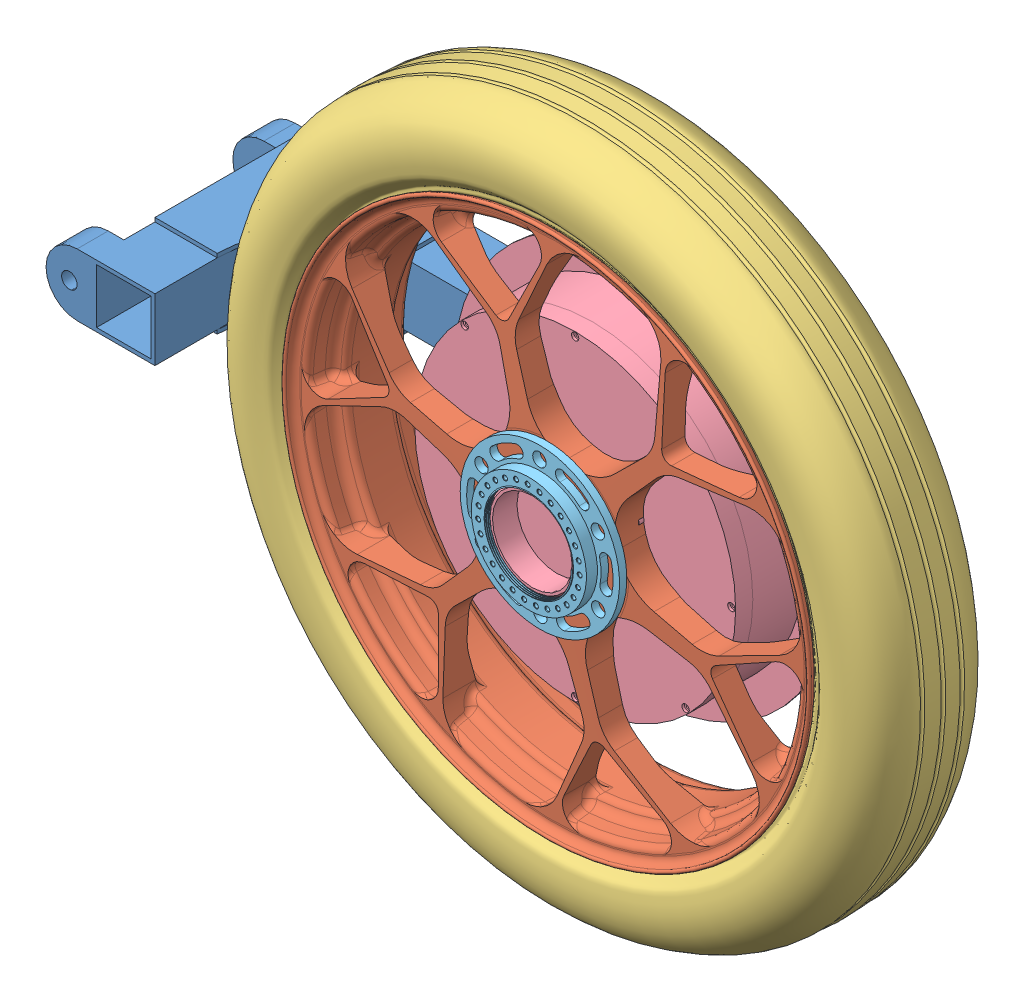
SolidWorks assembly Rear Suspension Assembly, configuration Default. Lengths in mm.
Overall size (682.53 577.66 234.56).
5 component instances, 5 part files, 35 mates.
Components (placement in the parent):
- Rear Fork V2-1: Rear Fork V2 [Default] at origin size (434.11 89.4 177.8)
- rimmachined13-1: rimmachined13 [Default] at (355.6 26.4753 117.375) x (0 0 1) z (0.95959 0.281401 0) size (93.59 431.57 431.57)
- Michelin Tire-2: Michelin Tire [Default] at (355.6 26.4753 117.375) x (0 0 -1) z (0.999256 0.038577 0) size (101.13 556.61 556.61)
- Motor Mitsuba M2096 D-III-1: Motor Mitsuba M2096 D-III [Default] at (355.6 26.4753 125.675) x (1 0 0) z (0 -1 0) size (310 108 310)
- Nut-2: Nut [Default] at (355.6 26.4753 186.0565) x (-1 0 0) z (0 0 -1) size (130 130 98.66)
Mates (geometry in assembly coordinates):
- Concentric2: concentric anti-aligned: cylinder of Spindle_Light-1 through (381 25.4 147.175) axis (0 0 1) radius 8.5; cylinder of SKF_6003-2Z.stp-1 through (381 25.4 143.9729) axis (0 0 -1) radius 8.5
- Concentric4: concentric aligned: cylinder of Hub-1 through (368.3 25.4 -790.8358) axis (0 0 -1) radius 21; cylinder of SKF_6004-2Z.stp-1 through (381 25.4 35.675) axis (0 0 -1) radius 21
- Coincident5: coincident anti-aligned: plane of Hub-1 through (387.1048 22.6835 123.775) normal (0 0 -1); plane of SKF_6004-2Z.stp-1 through (381 45.8 85.675) normal (0 0 1)
- Concentric5: concentric aligned: cylinder of Hub-1 through (368.3 25.4 -790.8358) axis (0 0 -1) radius 17.5; cylinder of SKF_6003-2Z.stp-1 through (381 25.4 143.9729) axis (0 0 -1) radius 17.5
- Coincident6: coincident anti-aligned: plane of Hub-1 through (383.6408 23.1839 158.775) normal (0 0 1); plane of SKF_6003-2Z.stp-1 through (382.3309 40.9431 183.9729) normal (0 0 -1)
- Coincident8: coincident anti-aligned: plane of Spindle_Light-1 through (381 37.4 73.675) normal (0 0 1); plane of SKF_6004-2Z.stp-1 through (381 36 73.675) normal (0 0 -1)
- Concentric6: concentric anti-aligned: cylinder of Hub-1 through (368.3 25.4 -790.8358) axis (0 0 -1) radius 47; cylinder of rimmachined13-1 through (355.6 26.4753 126.475) axis (0 0 1) radius 47
- Coincident9: coincident anti-aligned: plane of Hub-1 through (414.8171 18.6801 153.583) normal (0 0 1); plane of rimmachined13-1 through (366.8561 -11.9084 139.675) normal (0 0 -1)
- Perpendicular1: perpendicular: plane of Rear Fork V2-1 through (0 50.8 177.8) normal (0 1 0); plane of Spindle_Light-1 through (396 6.4835 47.175) normal (1 0 0)
- Concentric9: concentric aligned: cone of Hub-1 through (368.3 25.4 194.9918) axis (0 0 -1); cylinder of Nut-1 through (381 25.4 174.7059) axis (0 0 -1) radius 47
- Coincident13: coincident anti-aligned: plane of Nut-1 through (344.9044 19.9819 201.2743) normal (0 0 -1); plane of rimmachined13-1 through (373.8911 -35.8981 162.47) normal (0 0 1)
- Concentric14: concentric aligned: cylinder of rimmachined13-1 through (355.6 26.4753 31.8658) axis (0 0 -1) radius 192.7898; line of Michelin Tire-2 through (355.6 26.4753 220.0979) axis (0 0 -1)
- Coincident19: coincident: plane of rimmachined13-1 through (355.6 26.4753 117.375) normal (0 0 1); line of Michelin Tire-2 through (346.0008 275.1246 117.375) axis (0.038577 -0.999256 0)
- Concentric15: concentric aligned: cylinder of Hub-1 through (368.3 25.4 -790.8358) axis (0 0 -1) radius 29; cylinder of BasicBrakeDisc-1 through (673.6832 81.5008 299.6671) axis (0 0 -1) radius 28.956
- Coincident20: coincident anti-aligned: plane of Hub-1 through (397.0021 21.2537 113.775) normal (0 0 -1); plane of BasicBrakeDisc-1 through (673.6832 81.5008 299.6671) normal (0 0 1)
- Concentric16: concentric anti-aligned: cylinder of rimmachined13-1 through (355.6 26.4753 126.475) axis (0 0 1) radius 47; cylinder of Rear Hub-1 through (381 25.4 -765.5354) axis (0 0 -1) radius 47
- Coincident21: coincident anti-aligned: plane of rimmachined13-1 through (366.8561 -11.9084 139.675) normal (0 0 -1); plane of Rear Hub-1 through (428 25.4 178.4793) normal (0 0 1)
- Concentric17: concentric aligned: circle of Nut-1; cylinder of Rear Hub-1 through (381 25.4 -765.5354) axis (0 0 -1) radius 35.75
- Concentric18: concentric aligned: cylinder of SKF_6003-2Z.stp-1 through (381 25.4 143.9729) axis (0 0 -1) radius 17.5; cylinder of Rear Hub-1 through (381 25.4 -765.5354) axis (0 0 -1) radius 17.5
- Coincident22: coincident anti-aligned: plane of SKF_6003-2Z.stp-1 through (382.3309 40.9431 183.9729) normal (0 0 -1); plane of Rear Hub-1 through (396.5 25.4 183.9729) normal (0 0 1)
- Concentric19: concentric aligned: cylinder of SKF_6004-2Z.stp-1 through (381 25.4 35.675) axis (0 0 -1) radius 21; cylinder of Rear Hub-1 through (381 25.4 -765.5354) axis (0 0 -1) radius 21
- Coincident23: coincident anti-aligned: plane of SKF_6004-2Z.stp-1 through (381 45.8 85.675) normal (0 0 1); plane of Rear Hub-1 through (400 25.4 85.675) normal (0 0 -1)
- Concentric20: concentric anti-aligned: cylinder of Spindle_Light-1 through (381 25.4 147.175) axis (0 0 1) radius 10; circle of Rear Hub-1
- Parallel1: parallel anti-aligned: plane of Spindle_Light-1 through (381 42.4 71.675) normal (0 0 1); plane of SKF_6004-2Z.stp-1 through (381 36 73.675) normal (0 0 -1)
- Concentric21: concentric aligned: cylinder of BasicBrakeDisc-1 through (673.6832 81.5008 299.6671) axis (0 0 -1) radius 28.956; cylinder of Rear Hub-1 through (381 25.4 -765.5354) axis (0 0 -1) radius 48.8849
- Concentric23: concentric aligned: cylinder of Rear Fork V2-1 through (381 25.4 -9.525) axis (0 0 1) radius 10; cylinder of Spindle_Light-1 through (381 25.4 147.175) axis (0 0 1) radius 10
- Coincident28: coincident anti-aligned: plane of BasicBrakeDisc-1 through (673.6832 81.5008 299.6671) normal (0 0 1); plane of Rear Hub-1 through (410 25.4 75.675) normal (0 0 -1)
- Coincident29: coincident anti-aligned: plane of Rear Fork V2-1 through (0 -25.4 66.675) normal (0 0 1); plane of Spindle_Light-1 through (381 35.4 66.675) normal (0 0 -1)
- Concentric24: concentric anti-aligned: cylinder of rimmachined13-1 through (355.6 26.4753 126.475) axis (0 0 1) radius 47; cylinder of Motor Mitsuba M2096 D-III-1 through (355.6 26.4753 139.675) axis (0 0 -1) radius 47
- Coincident30: coincident anti-aligned: plane of rimmachined13-1 through (366.8561 -11.9084 139.675) normal (0 0 -1); plane of Motor Mitsuba M2096 D-III-1 through (355.6 26.4753 139.675) normal (0 0 1)
- Concentric25: concentric aligned: cylinder of Motor Mitsuba M2096 D-III-1 through (355.6 26.4753 161.175) axis (0 0 -1) radius 36.5; cylinder of Nut-2 through (355.6 26.4753 135.9016) axis (0 0 -1) radius 47
- Coincident31: coincident anti-aligned: plane of rimmachined13-1 through (373.8911 -35.8981 162.47) normal (0 0 1); plane of Nut-2 through (319.1 26.4753 162.47) normal (0 0 -1)
- Concentric28: concentric aligned: cylinder of Rear Fork V2-1 through (355.6 58.4753 0) axis (0 0 1) radius 4; cylinder of Motor Mitsuba M2096 D-III-1 through (355.6 58.4753 70.675) axis (0 0 1) radius 4
- Concentric29: concentric aligned: cylinder of Rear Fork V2-1 through (383.3128 42.4753 0) axis (0 0 1) radius 4; cylinder of Motor Mitsuba M2096 D-III-1 through (383.3128 42.4753 70.675) axis (0 0 1) radius 4
- Coincident33: coincident: plane of Rear Fork V2-1 through (0 -25.4 66.675) normal (0 0 1); plane of Motor Mitsuba M2096 D-III-1 through (342.9 25.4 66.675) normal (0 0 -1)
